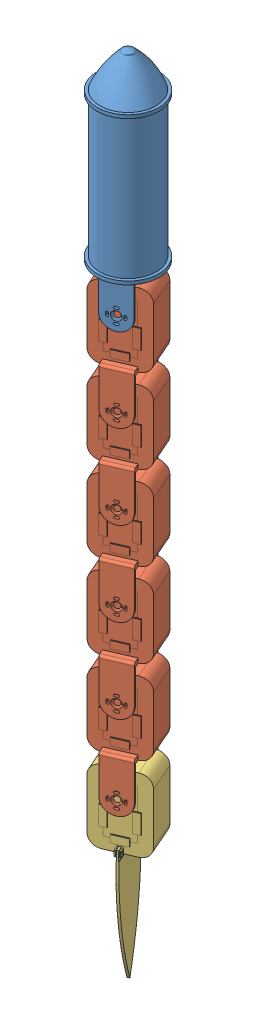
SolidWorks assembly 1fin_eel, configuration 預設. Lengths in mm.
Overall size (57.43 716.27 55.51).
7 component instances, 3 part files, 19 mates.
Components (placement in the parent):
- base_link-1: base_link [預設] at (-66.5632 -1.1579 104.9753) size (55 204.98 55)
- link2-1: link2 [預設] at (-45.8446 -161.6209 204.2877) x (0 1 0) z (0.399282 0 0.916828) size (107 45 40.5)
- link2-2: link2 [預設] at (-45.8446 -236.3209 204.2877) x (0 1 0) z (0.399282 0 0.916828) size (107 45 40.5)
- link2-3: link2 [預設] at (-45.8446 -311.0209 204.2877) x (0 1 0) z (0.399282 0 0.916828) size (107 45 40.5)
- link2-4: link2 [預設] at (-45.8446 -385.7209 204.2877) x (0 1 0) z (0.399282 0 0.916828) size (107 45 40.5)
- link2-5: link2 [預設] at (-45.8446 -460.4209 204.2877) x (0 1 0) z (0.399282 0 0.916828) size (107 45 40.5)
- 1fin_tail-1: 1fin_tail [預設] at (-69.3323 -465.8977 143.6201) x (0 1 0) z (0.399282 0 0.916828) size (170.09 45 38)
Mates (geometry in assembly coordinates):
- 同軸心1: concentric aligned: cylinder of base_link-1 through (-52.4327 -86.9209 189.16) axis (-0.399282 0 -0.916828) radius 2.7; cylinder of link2-1 through (-51.4345 -86.9209 191.4521) axis (-0.399282 0 -0.916828) radius 2.5
- 平行1: parallel aligned: plane of base_link-1 through (-42.6286 -56.9209 181.6182) normal (0.916828 0 -0.399282); plane of link2-1 through (-19.626 -131.6209 208.1394) normal (0.916828 0 -0.399282)
- 重合/共線/共點1: coincident aligned: circle of base_link-1; plane of link2-1 through (-38.2582 -86.9209 221.7074) normal (0.399282 0 0.916828)
- 重合/共線/共點2: coincident aligned: plane of link2-1 through (-60.8832 -131.6209 226.1071) normal (-0.916828 0 0.399282); plane of link2-2 through (-60.8832 -206.3209 226.1071) normal (-0.916828 0 0.399282)
- 同軸心2: concentric anti-aligned: cylinder of link2-1 through (-53.8302 -161.6209 185.9511) axis (0.399282 0 0.916828) radius 3.7; cylinder of link2-2 through (-51.4345 -161.6209 191.4521) axis (-0.399282 0 -0.916828) radius 2.5
- 平行2: parallel aligned: plane of link2-1 through (-54.7929 -154.5209 186.3704) normal (0 -1 0); plane of link2-2 through (-54.7929 -229.2209 186.3704) normal (0 -1 0)
- 重合/共線/共點4: coincident aligned: plane of link2-1 through (-51.4345 -71.6862 191.4521) normal (-0.399282 0 -0.916828); plane of link2-2 through (-51.4345 -146.3862 191.4521) normal (-0.399282 0 -0.916828)
- 重合/共線/共點5: coincident aligned: plane of link2-2 through (-60.8832 -206.3209 226.1071) normal (-0.916828 0 0.399282); plane of link2-3 through (-60.8832 -281.0209 226.1071) normal (-0.916828 0 0.399282)
- 同軸心3: concentric anti-aligned: cylinder of link2-2 through (-53.8302 -236.3209 185.9511) axis (0.399282 0 0.916828) radius 3.7; cylinder of link2-3 through (-51.4345 -236.3209 191.4521) axis (-0.399282 0 -0.916828) radius 2.5
- 重合/共線/共點6: coincident aligned: plane of link2-2 through (-53.8302 -146.3862 185.9511) normal (-0.399282 0 -0.916828); plane of link2-3 through (-53.8302 -221.0862 185.9511) normal (-0.399282 0 -0.916828)
- 重合/共線/共點7: coincident aligned: plane of link2-3 through (-60.8832 -281.0209 226.1071) normal (-0.916828 0 0.399282); plane of link2-4 through (-60.8832 -355.7209 226.1071) normal (-0.916828 0 0.399282)
- 同軸心4: concentric anti-aligned: cylinder of link2-3 through (-53.8302 -311.0209 185.9511) axis (0.399282 0 0.916828) radius 3.7; cylinder of link2-4 through (-51.4345 -311.0209 191.4521) axis (-0.399282 0 -0.916828) radius 2.5
- 重合/共線/共點8: coincident aligned: plane of link2-3 through (-51.4345 -221.0862 191.4521) normal (-0.399282 0 -0.916828); plane of link2-4 through (-51.4345 -295.7862 191.4521) normal (-0.399282 0 -0.916828)
- 重合/共線/共點10: coincident aligned: plane of link2-4 through (-51.4345 -295.7862 191.4521) normal (-0.399282 0 -0.916828); plane of link2-5 through (-51.4345 -370.4862 191.4521) normal (-0.399282 0 -0.916828)
- 重合/共線/共點11: coincident aligned: plane of link2-4 through (-60.8832 -355.7209 226.1071) normal (-0.916828 0 0.399282); plane of link2-5 through (-60.8832 -430.4209 226.1071) normal (-0.916828 0 0.399282)
- 同軸心6: concentric anti-aligned: cylinder of link2-4 through (-53.8302 -385.7209 185.9511) axis (0.399282 0 0.916828) radius 3.7; cylinder of link2-5 through (-51.4345 -385.7209 191.4521) axis (-0.399282 0 -0.916828) radius 2.5
- 重合/共線/共點12: coincident aligned: plane of link2-5 through (-60.8832 -430.4209 226.1071) normal (-0.916828 0 0.399282); plane of 1fin_tail-1 through (-60.8832 -505.1209 226.1071) normal (-0.916828 0 0.399282)
- 同軸心7: concentric aligned: cylinder of link2-5 through (-53.8302 -460.4209 185.9511) axis (0.399282 0 0.916828) radius 3.7; cylinder of 1fin_tail-1 through (-53.4309 -460.4209 186.868) axis (0.399282 0 0.916828) radius 2.5
- 重合/共線/共點13: coincident aligned: plane of link2-5 through (-51.4345 -370.4862 191.4521) normal (-0.399282 0 -0.916828); plane of 1fin_tail-1 through (-51.4345 -445.1862 191.4521) normal (-0.399282 0 -0.916828)
